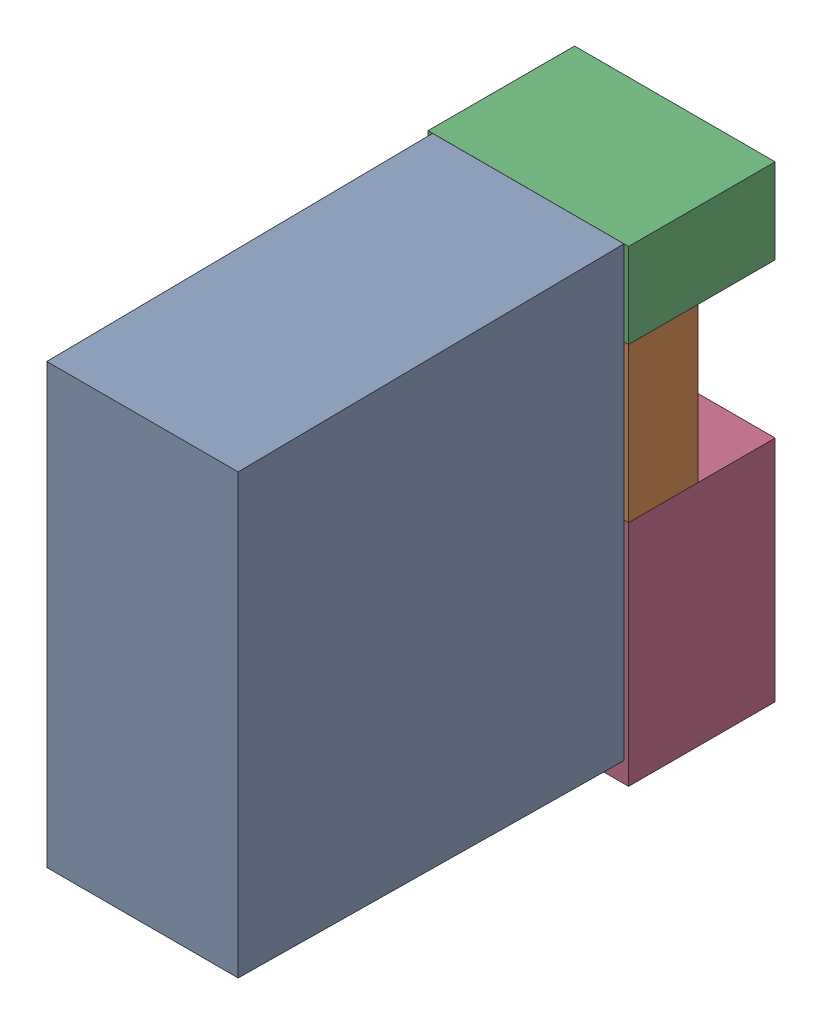
SolidWorks assembly K10, configuration Default. Lengths in mm.
Overall size (13 30.3 34.5).
7 component instances, 4 part files, 0 mates.
Components (placement in the parent):
- relais_40_61_8_006_0000-1: relais_40_61_8_006_0000 [Default] at (144.145 15.7216 9.5) x (0 1 0) z (1 0 0) size (29 30 12.4)
- 1151725064-1: 1151725064 [Default] at (144.145 34.225 5) size (13 10 4.5)
  - Extruded_3-1: Extruded_3 [Default] at origin size (13 10 4.5)
- 1151724928-1: 1151724928 [Default] at (144.145 41.975 0) size (13 5.5 9.5)
  - Extruded_2-1: Extruded_2 [Default] at origin size (13 5.5 9.5)
- 1151724792-1: 1151724792 [Default] at (144.145 21.825 0) size (13 14.8 9.5)
  - Extruded_4-1: Extruded_4 [Default] at origin size (13 14.8 9.5)
